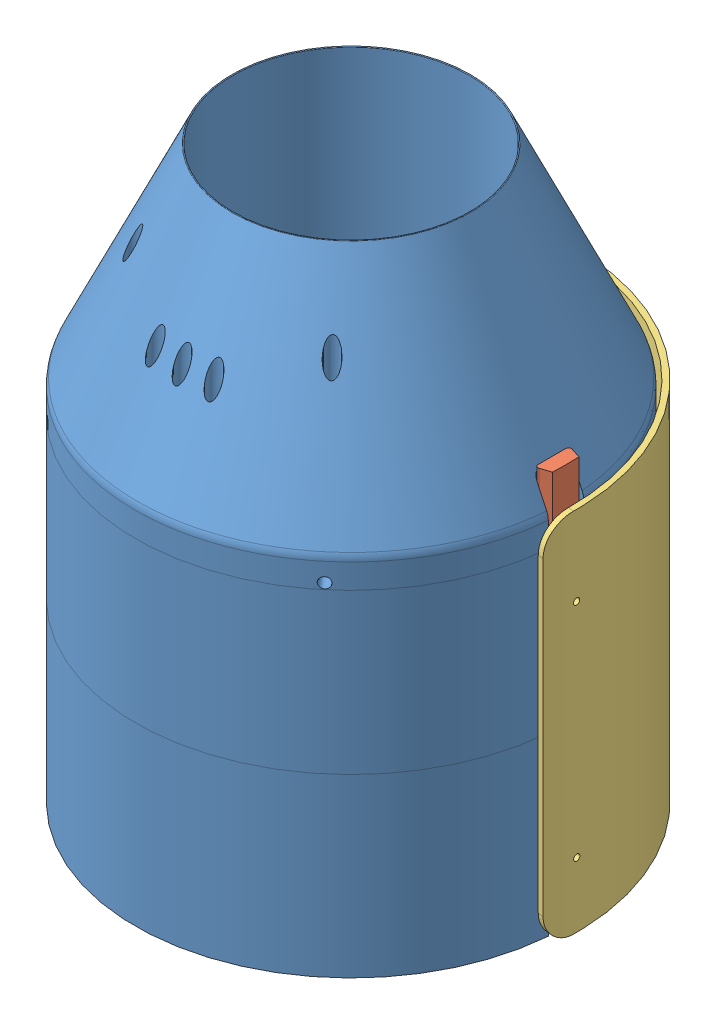
SolidWorks assembly Drogue with bigger hatch, configuration Default. Lengths in mm.
Overall size (203.35 257.94 198.75).
4 component instances, 3 part files, 6 mates.
Components (placement in the parent):
- Drogue Pods V5 (1)-1: Drogue Pods V5 (1) [Default] at (-43.9996 -114.9745 16.2248) size (194.51 257.12 194.47)
- Hea Set Insert Sled V2-1: Hea Set Insert Sled V2 [Default] at (249.6776 -116.0698 16.1217) x (0 -0.000707 1) z (-1 0 0) size (15.05 178 6.39)
- Hea Set Insert Sled V2-2: Hea Set Insert Sled V2 [Default] at (-337.6767 -116.0698 16.1217) x (0 0.000707 -1) z (1 0 0) size (15.05 178 6.39)
- Bigger_Hatch-2: Bigger_Hatch [Default] at (-43.9996 -118.2544 16.2248) size (203.35 166.54 116.46)
Mates (geometry in assembly coordinates):
- Coincident1: coincident anti-aligned: plane of Drogue Pods V5 (1)-1 through (46.4776 138.9676 16.2248) normal (1 0 0); plane of Hea Set Insert Sled V2-1 through (46.4776 61.9245 24.2485) normal (-1 0 0)
- Concentric1: concentric aligned: cylinder of Drogue Pods V5 (1)-1 through (33.7776 29.8055 16.2248) axis (1 0 0) radius 2.0955; cylinder of Hea Set Insert Sled V2-1 through (52.8276 29.8055 16.2248) axis (1 0 0) radius 1.632
- Coincident2: coincident anti-aligned: plane of Drogue Pods V5 (1)-1 through (-134.4767 138.9676 16.2248) normal (-1 0 0); plane of Hea Set Insert Sled V2-2 through (-134.4767 61.9358 8.2466) normal (1 0 0)
- Concentric2: concentric aligned: cylinder of Drogue Pods V5 (1)-1 through (-126.8567 29.8055 16.2248) axis (-1 0 0) radius 2.0955; cylinder of Hea Set Insert Sled V2-2 through (-140.8267 29.8055 16.2248) axis (-1 0 0) radius 1.632
- Concentric5: concentric aligned: cylinder of Drogue Pods V5 (1)-1 through (-43.9996 165.9935 16.2248) axis (0 -1 0) radius 97.155; cylinder of Bigger_Hatch-2 through (-43.9996 46.8456 16.2248) axis (0 -1 0) radius 99.06
- Concentric6: concentric aligned: cylinder of Hea Set Insert Sled V2-1 through (46.4776 -89.0698 16.1408) axis (1 0 0) radius 1.397; cylinder of Bigger_Hatch-2 through (-145.5996 -89.0698 16.1408) axis (1 0 0) radius 1.397
